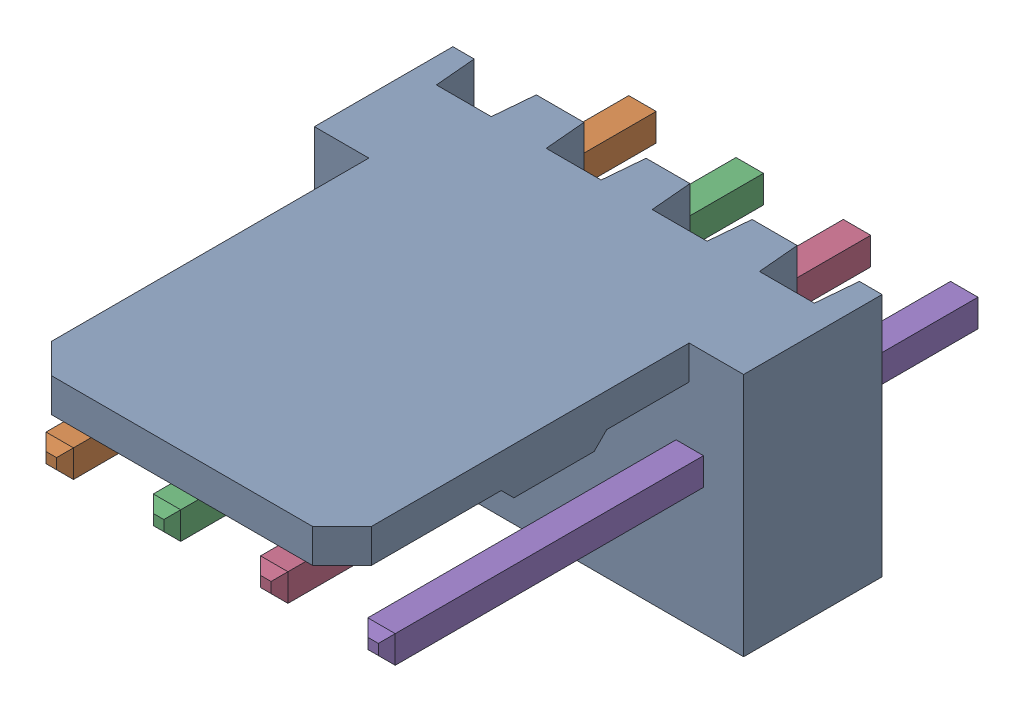
SolidWorks assembly Molex PCB 4 pin v3_7, configuration Predeterminado. Lengths in mm.
Overall size (10.16 5.79 14.92).
5 component instances, 2 part files, 0 mates.
Components (placement in the parent):
- BASE9710016-1: BASE9710016 [Predeterminado] at (2.54 2.895 -8.22) size (10.16 5.79 11.5)
- PINO9710016-1: PINO9710016 [Predeterminado] at (1.27 3.325 -0.72) size (0.65 0.65 14.2)
- PINO9710016-2: PINO9710016 [Predeterminado] at (3.81 3.325 -0.72) size (0.65 0.65 14.2)
- PINO9710016-3: PINO9710016 [Predeterminado] at (6.35 3.325 -0.72) size (0.65 0.65 14.2)
- PINO9710016-4: PINO9710016 [Predeterminado] at (8.89 3.325 -0.72) size (0.65 0.65 14.2)
